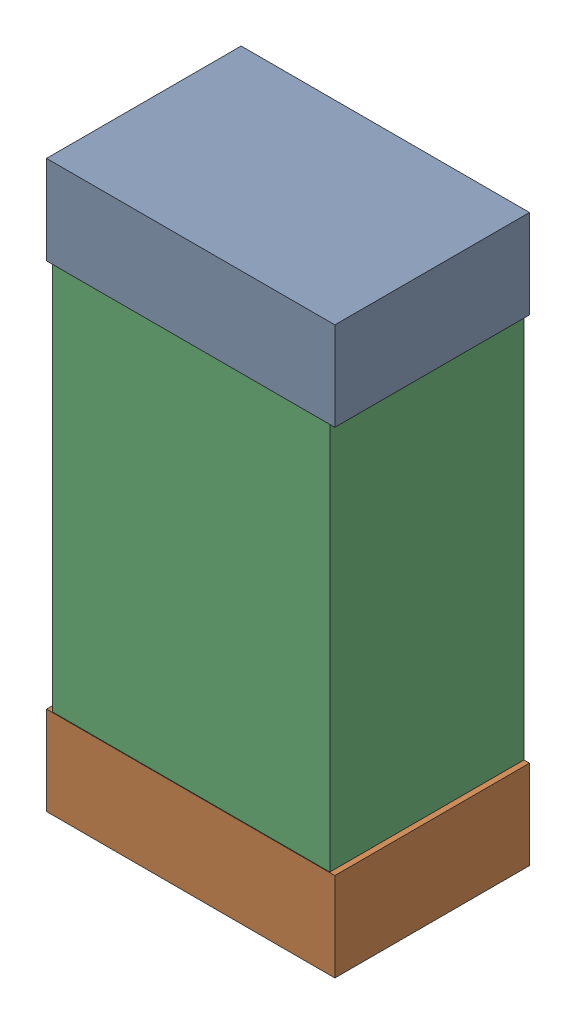
SolidWorks assembly C9, configuration Default. Lengths in mm.
Overall size (0.52 1.02 0.35).
6 component instances, 2 part files, 0 mates.
Components (placement in the parent):
- 870941120-1: 870941120 [Default] at (60.0448 26.4882 0) size (0.52 0.16 0.35)
  - Extruded_3-1: Extruded_3 [Default] at origin size (0.52 0.16 0.35)
- 870941120-2: 870941120 [Default] at (60.0448 25.6282 0) size (0.52 0.16 0.35)
  - Extruded_3-1: Extruded_3 [Default] at origin size (0.52 0.16 0.35)
- 870941280-1: 870941280 [Default] at (60.0448 26.0582 0) size (0.5 1 0.35)
  - Extruded_4-1: Extruded_4 [Default] at origin size (0.5 1 0.35)
